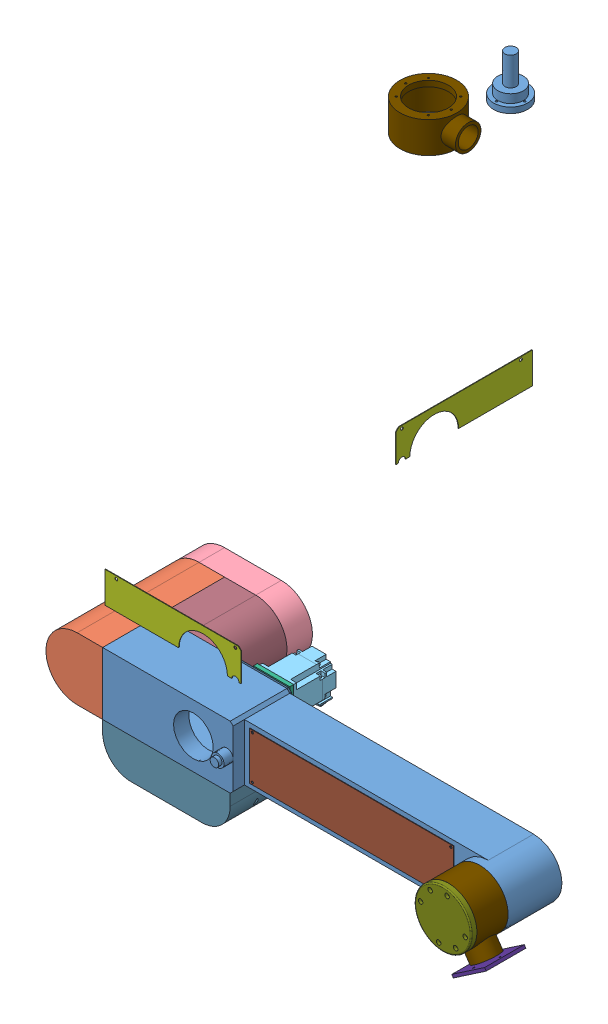
SolidWorks assembly Assem1, configuration Default. Lengths in mm.
Overall size (1020.58 553.13 1028.9).
21 component instances, 19 part files, 45 mates.
Components (placement in the parent):
- [K3]Thân.stp-1: [K3]Thân.stp [Default] at (186.1601 388.6634 574.2727) size (710 110 122)
- [K3[Nắp.stp-1: [K3[Nắp.stp [Default] at (-18.8399 388.6634 594.2727) x (0 0 -1) z (1 0 0) size (215 110 100)
- [K3]Căn_chỉnh_ĐC.stp-1: [K3]Căn_chỉnh_ĐC.stp [Default] at (-18.8399 388.6634 381.7727) x (0 1 0) z (-1 0 0) size (88 2.5 80)
- [K3]Đỡ DC.stp-1: [K3]Đỡ DC.stp [Default] at (81.1601 388.6634 379.2727) x (0 0 -1) z (1 0 0) size (45 110 210)
- [K3]Động_cơ.stp-1: [K3]Động_cơ.stp [Default] at (196.1601 388.6634 459.2727) size (60 68.8 106.6)
- [K3]Mặt_Bích.stp-1: [K3]Mặt_Bích.stp [Default] at (196.1601 388.6634 459.2727) x (1 0 0) z (0 -1 0) size (64 32 64)
- [K3]Nap.stp-1: [K3]Nap.stp [Default] at (261.0338 501.0343 585.1185) x (0 0 -1) z (1 0 0) size (1 55 240)
- [K3]Nắp_Đầu.stp-1: [K3]Nắp_Đầu.stp [Default] at (686.1601 388.6634 494.2727) x (0 0 1) z (-1 0 0) size (1 94.92 95)
- [K3]Nắp_Đỡ DC.stp-1: [K3]Nắp_Đỡ DC.stp [Default] at (31.1601 388.6634 333.2727) x (0 0 1) z (-1 0 0) size (1 105 205)
- [K3]Nắp_ĐộngCơ.stp-1: [K3]Nắp_ĐộngCơ.stp [Default] at (196.1601 388.6634 491.2727) x (0 0 1) z (-1 0 0) size (3 110 120)
- [K3]Nắp_Thân.stp-1: [K3]Nắp_Thân.stp [Default] at (446.1601 388.6634 575.2727) x (0 -1 0) z (1 0 0) size (84 1 360)
- [K3]Nắp_Thân_22.stp-1: [K3]Nắp_Thân_22.stp [Default] at (446.1601 389.1634 493.2727) x (0 -1 0) z (-1 0 0) size (88 1 370)
- [K3]Ong.stp-1: [K3]Ong.stp [Default] at (81.1601 388.6634 494.2727) x (0 0 -1) z (1 0 0) size (115 110 110)
- [K3]Ốp.stp-1: [K3]Ốp.stp [Default] at (138.6601 263.6634 544.2727) x (0 0 -1) z (1 0 0) size (100 70 225)
- [K4]Động_cơ.stp-1: [K4]Động_cơ.stp [Default] at (-8.8399 388.6634 381.7727) x (0 1 0) z (0 0 -1) size (60 68.8 106.6)
- [K4]Nắp.stp-1: [K4]Nắp.stp [Default] at (686.1601 388.6634 644.2727) x (0.826761 0.562554 0) z (0.562554 -0.826761 0) size (100 10 100)
- [K4]Tam noi.stp-1: [K4]Tam noi.stp [Default] at (728.6608 329.8401 617.2103) x (0 0 -1) z (-0.826761 -0.562554 0) size (70 5 70)
- [K4]Thân.stp-1: [K4]Thân.stp [Default] at (686.1601 388.6634 616.7727) x (0.562554 -0.826761 0) z (-0.826761 -0.562554 0) size (120 55 100)
- [K4]Thân.stp-2: [K4]Thân.stp [Default] at (-203.7064 740.4348 -210.198) size (120 55 100)
- [K4]Trục.stp-1: [K4]Trục.stp [Default] at (-193.3121 700.9983 -344.6302) size (60 75 60)
- [K3]Nap.stp-2: [K3]Nap.stp [Default] at (322.7939 761.7898 374.1718) size (1 55 240)
Mates (geometry in assembly coordinates):
- Coincident1: coincident anti-aligned: plane of [K3]Thân.stp-1 through (251.1601 333.6634 574.2727) normal (0 -1 0); plane of [K3]Ốp.stp-1 through (26.1601 333.6634 544.2727) normal (0 1 0)
- Coincident2: coincident aligned: plane of [K3]Thân.stp-1 through (26.1601 333.6634 574.2727) normal (-1 0 0); plane of [K3]Ốp.stp-1 through (26.1601 313.6634 544.2727) normal (-1 0 0)
- Coincident3: coincident aligned: plane of [K3]Thân.stp-1 through (141.1601 388.6634 594.2727) normal (0 0 1); plane of [K3]Ốp.stp-1 through (138.6601 298.6634 594.2727) normal (0 0 1)
- Coincident4: coincident aligned: plane of [K3]Thân.stp-1 through (141.1601 388.6634 594.2727) normal (0 0 1); plane of [K3[Nắp.stp-1 through (-23.8399 388.6634 594.2727) normal (0 0 1)
- Coincident5: coincident anti-aligned: plane of [K3]Thân.stp-1 through (26.1601 333.6634 574.2727) normal (-1 0 0); plane of [K3[Nắp.stp-1 through (26.1601 443.6634 594.2727) normal (1 0 0)
- Coincident6: coincident aligned: plane of [K3]Thân.stp-1 through (26.1601 443.6634 574.2727) normal (0 1 0); plane of [K3[Nắp.stp-1 through (-18.8399 443.6634 594.2727) normal (0 1 0)
- Coincident7: coincident anti-aligned: plane of [K3]Thân.stp-1 through (461.1601 388.6634 494.2727) normal (0 0 -1); plane of [K3]Ong.stp-1 through (81.1601 388.6634 494.2727) normal (0 0 1)
- Coincident8: coincident aligned: plane of [K3]Thân.stp-1 through (26.1601 443.6634 574.2727) normal (0 1 0); plane of [K3]Ong.stp-1 through (26.1601 443.6634 494.2727) normal (0 1 0)
- Coincident9: coincident aligned: plane of [K3]Thân.stp-1 through (26.1601 333.6634 574.2727) normal (-1 0 0); plane of [K3]Ong.stp-1 through (26.1601 333.6634 494.2727) normal (-1 0 0)
- Coincident10: coincident anti-aligned: plane of [K3]Thân.stp-1 through (461.1601 388.6634 494.2727) normal (0 0 -1); plane of [K3]Nắp_ĐộngCơ.stp-1 through (196.1601 388.6634 494.2727) normal (0 0 1)
- Concentric1: concentric anti-aligned: circle of [K3]Thân.stp-1; cylinder of [K3]Nắp_ĐộngCơ.stp-1 through (196.1601 388.6634 494.2727) axis (0 0 -1) radius 20
- Coincident11: coincident aligned: plane of [K3]Thân.stp-1 through (26.1601 443.6634 574.2727) normal (0 1 0); plane of [K3]Nắp_ĐộngCơ.stp-1 through (256.1601 443.6634 491.2727) normal (0 1 0)
- Parallel1: parallel aligned: plane of [K4]Tam noi.stp-1 through (757.5974 349.5295 652.2103) normal (0 0 1); plane of [K4]Thân.stp-1 through (686.1601 388.6634 644.2727) normal (0 0 1)
- Coincident14: coincident anti-aligned: plane of [K4]Nắp.stp-1 through (686.1601 388.6634 644.2727) normal (0 0 -1); plane of [K4]Thân.stp-1 through (686.1601 388.6634 644.2727) normal (0 0 1)
- Concentric2: concentric aligned: cylinder of [K4]Nắp.stp-1 through (663.6579 421.7338 509.9982) axis (0 0 1) radius 2.25; cylinder of [K4]Thân.stp-1 through (663.6579 421.7338 478.6677) axis (0 0 1) radius 1.621
- Concentric3: concentric aligned: cylinder of [K4]Nắp.stp-1 through (708.6622 355.5929 509.9982) axis (0 0 1) radius 2.25; cylinder of [K4]Thân.stp-1 through (708.6622 355.5929 478.6677) axis (0 0 1) radius 1.621
- Coincident16: coincident anti-aligned: plane of [K3]Thân.stp-1 through (686.1601 388.6634 589.2727) normal (0 0 1); plane of [K4]Thân.stp-1 through (686.1601 388.6634 589.2727) normal (0 0 -1)
- Concentric4: concentric aligned: cylinder of [K3]Thân.stp-1 through (686.1601 388.6634 574.2727) axis (0 0 -1) radius 50; cylinder of [K4]Thân.stp-1 through (686.1601 388.6634 611.7727) axis (0 0 -1) radius 45
- Concentric5: concentric anti-aligned: cylinder of [K3]Thân.stp-1 through (196.1601 388.6634 497.7727) axis (0 0 -1) radius 15; cylinder of [K3]Động_cơ.stp-1 through (196.1601 388.6634 475.7727) axis (0 0 1) radius 7
- Parallel2: parallel aligned: plane of [K3]Thân.stp-1 through (26.1601 443.6634 574.2727) normal (0 1 0); plane of [K3]Động_cơ.stp-1 through (196.1601 418.6634 432.9727) normal (0 1 0)
- Coincident20: coincident anti-aligned: plane of [K3]Căn_chỉnh_ĐC.stp-1 through (-18.8399 388.6634 379.2727) normal (0 0 -1); plane of [K3]Đỡ DC.stp-1 through (31.1601 388.6634 379.2727) normal (0 0 1)
- Concentric10: concentric anti-aligned: cylinder of [K3]Căn_chỉnh_ĐC.stp-1 through (-8.8399 388.6634 381.7727) axis (0 0 -1) radius 25; cylinder of [K3]Đỡ DC.stp-1 through (-8.8399 388.6634 374.2727) axis (0 0 1) radius 20
- Parallel3: parallel aligned: plane of [K3]Căn_chỉnh_ĐC.stp-1 through (-40.8399 432.6634 381.7727) normal (0 1 0); plane of [K3]Đỡ DC.stp-1 through (-18.8399 443.6634 379.2727) normal (0 1 0)
- Concentric11: concentric anti-aligned: cylinder of [K3]Đỡ DC.stp-1 through (-8.8399 388.6634 374.2727) axis (0 0 1) radius 20; cylinder of [K4]Động_cơ.stp-1 through (-8.8399 388.6634 365.2727) axis (0 0 -1) radius 7
- Parallel4: parallel: line of [K3]Căn_chỉnh_ĐC.stp-1 through (16.1601 428.6634 379.2727) axis (-1 0 0); plane of [K4]Động_cơ.stp-1 through (-8.8399 418.6634 408.0727) normal (0 1 0)
- Coincident23: coincident anti-aligned: plane of [K3]Căn_chỉnh_ĐC.stp-1 through (-18.8399 388.6634 381.7727) normal (0 0 1); plane of [K4]Động_cơ.stp-1 through (-8.8399 388.6634 381.7727) normal (0 0 -1)
- Coincident24: coincident anti-aligned: plane of [K3]Đỡ DC.stp-1 through (31.1601 388.6634 379.2727) normal (0 0 1); plane of [K3]Ong.stp-1 through (81.1601 388.6634 379.2727) normal (0 0 -1)
- Concentric12: concentric aligned: cylinder of [K3]Đỡ DC.stp-1 through (81.1601 388.6634 379.2727) axis (0 0 -1) radius 55; cylinder of [K3]Ong.stp-1 through (81.1601 388.6634 483.2727) axis (0 0 -1) radius 55
- Concentric13: concentric aligned: cylinder of [K3[Nắp.stp-1 through (-18.8399 388.6634 594.2727) axis (0 0 -1) radius 55; cylinder of [K3]Đỡ DC.stp-1 through (-18.8399 388.6634 379.2727) axis (0 0 -1) radius 55
- Coincident25: coincident anti-aligned: plane of [K3]Đỡ DC.stp-1 through (31.1601 388.6634 334.2727) normal (0 0 -1); plane of [K3]Nắp_Đỡ DC.stp-1 through (31.1601 388.6634 334.2727) normal (0 0 1)
- Concentric14: concentric anti-aligned: cylinder of [K3]Đỡ DC.stp-1 through (81.1601 388.6634 379.2727) axis (0 0 -1) radius 55; cylinder of [K3]Nắp_Đỡ DC.stp-1 through (81.1601 388.6634 333.2727) axis (0 0 1) radius 52.5
- Concentric15: concentric anti-aligned: cylinder of [K3]Đỡ DC.stp-1 through (-18.8399 388.6634 379.2727) axis (0 0 -1) radius 55; cylinder of [K3]Nắp_Đỡ DC.stp-1 through (-18.8399 388.6634 333.2727) axis (0 0 1) radius 52.5
- Coincident26: coincident anti-aligned: plane of [K3]Mặt_Bích.stp-1 through (196.1601 388.6634 491.2727) normal (0 0 1); plane of [K3]Nắp_ĐộngCơ.stp-1 through (196.1601 388.6634 491.2727) normal (0 0 -1)
- Concentric16: concentric aligned: cylinder of [K3]Mặt_Bích.stp-1 through (171.4114 413.4121 395.2727) axis (0 0 1) radius 2.067; cylinder of [K3]Nắp_ĐộngCơ.stp-1 through (171.4114 413.4121 331.4568) axis (0 0 1) radius 2.067
- Parallel5: parallel aligned: plane of [K3]Thân.stp-1 through (26.1601 443.6634 574.2727) normal (0 1 0); plane of [K3]Mặt_Bích.stp-1 through (228.1601 420.6634 484.2727) normal (0 1 0)
- Coincident28: coincident anti-aligned: plane of [K3]Động_cơ.stp-1 through (196.1601 388.6634 459.2727) normal (0 0 1); plane of [K3]Mặt_Bích.stp-1 through (196.1601 388.6634 459.2727) normal (0 0 -1)
- Concentric17: concentric anti-aligned: cylinder of [K3]Thân.stp-1 through (686.1601 388.6634 567.2727) axis (0 0 -1) radius 42.5; cylinder of [K3]Nắp_Đầu.stp-1 through (686.1601 388.6634 494.2727) axis (0 0 1) radius 47.5
- Coincident29: coincident aligned: plane of [K3]Thân.stp-1 through (461.1601 388.6634 494.2727) normal (0 0 -1); plane of [K3]Nắp_Đầu.stp-1 through (686.1601 388.6634 494.2727) normal (0 0 -1)
- Concentric18: concentric anti-aligned: cylinder of [K3]Thân.stp-1 through (686.1601 343.6634 1218.1834) axis (0 0 -1) radius 1.621; cylinder of [K3]Nắp_Đầu.stp-1 through (686.1601 343.6634 494.2727) axis (0 0 1) radius 2
- Coincident32: coincident: plane of [K3]Thân.stp-1 through (461.1601 388.6634 574.2727) normal (0 0 1); plane of [K3]Nắp_Thân.stp-1 through (446.1601 388.6634 574.2727) normal (0 0 -1)
- Concentric20: concentric: cylinder of [K3]Thân.stp-1 through (621.1601 426.6634 1217.1834) axis (0 0 -1) radius 1.621; cylinder of [K3]Nắp_Thân.stp-1 through (621.1601 426.6634 943.9441) axis (0 0 -1) radius 2
- Concentric21: concentric aligned: cylinder of [K3]Thân.stp-1 through (271.1601 426.6634 1217.1834) axis (0 0 -1) radius 1.621; cylinder of [K3]Nắp_Thân.stp-1 through (271.1601 426.6634 943.9441) axis (0 0 -1) radius 2
- Coincident33: coincident: plane of [K3]Thân.stp-1 through (461.1601 388.6634 494.2727) normal (0 0 -1); plane of [K3]Nắp_Thân_22.stp-1 through (446.1601 389.1634 494.2727) normal (0 0 1)
- Concentric22: concentric: cylinder of [K3]Thân.stp-1 through (621.1601 426.6634 1217.1834) axis (0 0 -1) radius 1.621; cylinder of [K3]Nắp_Thân_22.stp-1 through (621.1601 426.6634 113.9504) axis (0 0 1) radius 2
- Concentric23: concentric anti-aligned: cylinder of [K3]Thân.stp-1 through (446.1601 426.6634 1217.1834) axis (0 0 -1) radius 1.621; cylinder of [K3]Nắp_Thân_22.stp-1 through (446.1601 426.6634 113.9504) axis (0 0 1) radius 2
